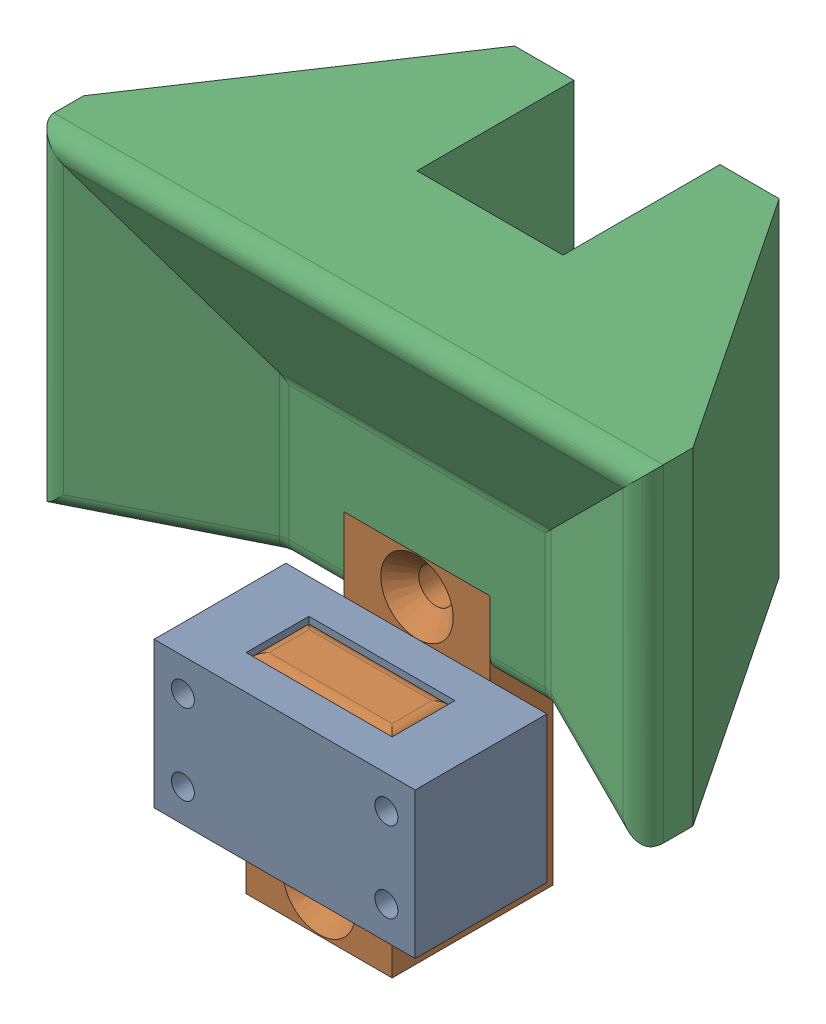
SolidWorks assembly SalmonLadderFit, configuration Default. Lengths in mm.
Overall size (45.4 49.02 33.94).
3 component instances, 3 part files, 6 mates.
Components (placement in the parent):
- CutoutBracket-1: CutoutBracket [Default] at (48.7397 12.958 16.9737) size (45.4 25.4 22.92)
- HookBracket-1: HookBracket [Default] at (36.0397 22.8995 10.5419) size (25.4 49.02 27.94)
- Guide-1: Guide [Default] at (48.7397 52.558 5.4127) size (106 57 53.15) (hidden)
Mates (geometry in assembly coordinates):
- LimitDistance2: limit distance = 0 mm anti-aligned: plane of CutoutBracket-1 through (36.0397 38.358 11.5127) normal (0 0 1); plane of HookBracket-1 through (61.4397 38.358 11.5127) normal (0 0 -1)
- Coincident2: coincident anti-aligned: plane of CutoutBracket-1 through (36.0397 38.358 22.4347) normal (1 0 0); plane of HookBracket-1 through (36.0397 22.8995 10.5419) normal (-1 0 0)
- LimitDistance1: limit distance = 0 mm anti-aligned: plane of CutoutBracket-1 through (48.7397 12.958 16.9737) normal (0 -1 0); plane of HookBracket-1 through (61.4397 12.958 5.4127) normal (0 1 0)
- Coincident10: coincident anti-aligned: plane of HookBracket-1 through (61.4397 51.058 -5.5093) normal (0 1 0); plane of Guide-1 through (48.7397 51.058 5.4127) normal (0 -1 0)
- Coincident11: coincident anti-aligned: plane of HookBracket-1 through (61.4397 22.8995 10.5419) normal (1 0 0); plane of Guide-1 through (61.4397 51.058 5.4127) normal (-1 0 0)
- Coincident12: coincident aligned: plane of HookBracket-1 through (61.4397 51.058 5.4127) normal (0 0 1); plane of Guide-1 through (48.7397 52.558 5.4127) normal (0 0 1)
